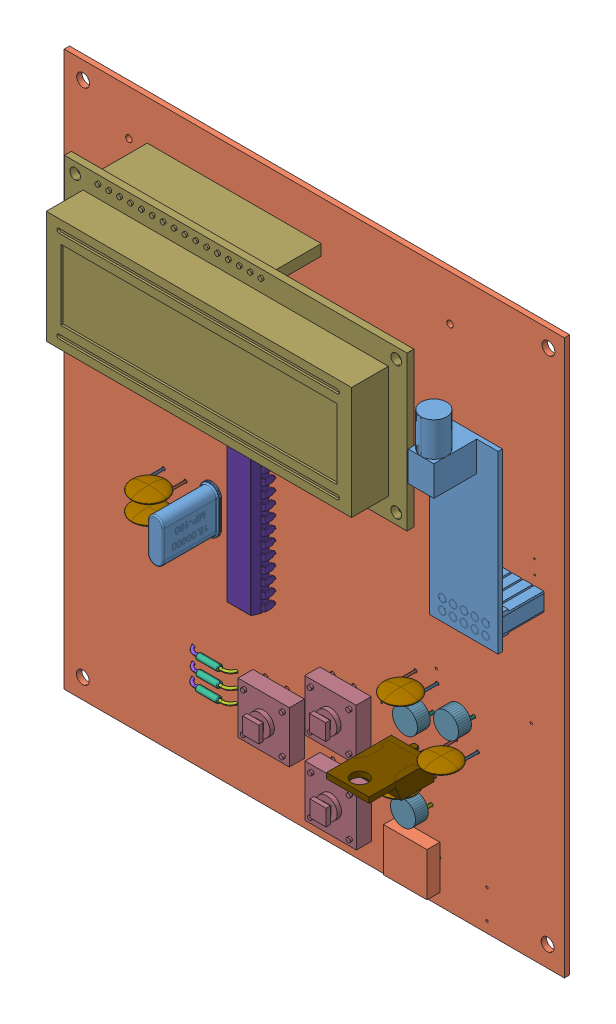
SolidWorks assembly Handheld Terminal Circuit, configuration Default. Lengths in mm.
Overall size (116.81 129.48 32.4).
99 component instances, 20 part files, 0 mates.
Components (placement in the parent):
- Handheld Terminal Circuit.STEP-1: Handheld Terminal Circuit.STEP [Default] at origin size (116.81 129.48 32.4)
  - X1.STEP-1: X1.STEP [Default] at (-24.8494 -12.1588 0.625) x (0 1 0) z (0 0 1) size (11 4.5 15.2)
    - Open CASCADE STEP translator 6.8 1.2.1.STEP-1: Open CASCADE STEP translator 6.8 1.2.1.STEP [Default] at origin size (11 4.5 15.2)
      - Body_1.STEP-1: Body_1.STEP [Default] at (2.5 0 0) x (1 0 0) z (0 -1 0) size (11 15.2 4.5)
  - J1.STEP-1: J1.STEP [Default] at (27.8456 -53.6484 0.625) x (-1 0 0) z (0 0 1) size (10.16 10.16 8.71)
    - Open CASCADE STEP translator 6.8 1.3.1.STEP-1: Open CASCADE STEP translator 6.8 1.3.1.STEP [Default] at origin size (10.16 10.16 8.71)
      - Body_1-0.STEP-1: Body_1-0.STEP [Default] at origin size (10.16 10.16 3)
      - Pin_1.STEP-1: Pin_1.STEP [Default] x (0 -1 0) z (0 0 1) size (1.42 1.42 7.92)
      - Pin_2.STEP-1: Pin_2.STEP [Default] at (5.08 5.08 0) x (0 -1 0) z (0 0 1) size (1.42 1.42 7.92)
  - U2.STEP-1: U2.STEP [Default] at (37.1858 -34.3162 -0.625) x (0 -1 0) z (0 0 -1) size (3.55 6.6 1.62)
    - Open CASCADE STEP translator 6.8 1.4.1.STEP-1: Open CASCADE STEP translator 6.8 1.4.1.STEP [Default] at origin size (3.55 6.6 1.62)
      - Body_1-1.STEP-1: Body_1-1.STEP [Default] at origin size (3.55 6.6 1.62)
  - R1.STEP-1: R1.STEP [Default] at (-50.4294 44.6446 0.625) x (0 -1 0) z (0 0 1) size (10.82 1.37 5.33)
    - Open CASCADE STEP translator 6.8 1.5.1.STEP-1: Open CASCADE STEP translator 6.8 1.5.1.STEP [Default] at origin size (10.82 1.37 5.33)
      - Body_1-2.STEP-1: Body_1-2.STEP [Default] at origin size (5.08 1.37 1.37)
      - Pin_1-3.STEP-1: Pin_1-3.STEP [Default] at origin size (3.2 0.66 4.98)
      - Pin_2-4.STEP-1: Pin_2-4.STEP [Default] at (20.32 0 0) x (-1 0 0) z (0 0 1) size (3.2 0.66 4.98)
  - R2.STEP-1: R2.STEP [Default] at (-20.066 15.8496 0.625) size (10.82 1.37 5.33)
    - Open CASCADE STEP translator 6.8 1.5.1.STEP-1: Open CASCADE STEP translator 6.8 1.5.1.STEP [Default] at origin size (10.82 1.37 5.33)
      - Body_1-2.STEP-1: Body_1-2.STEP [Default] at origin size (5.08 1.37 1.37)
      - Pin_1-3.STEP-1: Pin_1-3.STEP [Default] at origin size (3.2 0.66 4.98)
      - Pin_2-4.STEP-1: Pin_2-4.STEP [Default] at (20.32 0 0) x (-1 0 0) z (0 0 1) size (3.2 0.66 4.98)
  - R3.STEP-1: R3.STEP [Default] at (-19.1008 -43.1546 0.625) x (-1 0 0) z (0 0 1) size (10.82 1.37 5.33)
    - Open CASCADE STEP translator 6.8 1.5.1.STEP-1: Open CASCADE STEP translator 6.8 1.5.1.STEP [Default] at origin size (10.82 1.37 5.33)
      - Body_1-2.STEP-1: Body_1-2.STEP [Default] at origin size (5.08 1.37 1.37)
      - Pin_1-3.STEP-1: Pin_1-3.STEP [Default] at origin size (3.2 0.66 4.98)
      - Pin_2-4.STEP-1: Pin_2-4.STEP [Default] at (20.32 0 0) x (-1 0 0) z (0 0 1) size (3.2 0.66 4.98)
  - R4.STEP-1: R4.STEP [Default] at (-19.1008 -39.751 0.625) x (-1 0 0) z (0 0 1) size (10.82 1.37 5.33)
    - Open CASCADE STEP translator 6.8 1.5.1.STEP-1: Open CASCADE STEP translator 6.8 1.5.1.STEP [Default] at origin size (10.82 1.37 5.33)
      - Body_1-2.STEP-1: Body_1-2.STEP [Default] at origin size (5.08 1.37 1.37)
      - Pin_1-3.STEP-1: Pin_1-3.STEP [Default] at origin size (3.2 0.66 4.98)
      - Pin_2-4.STEP-1: Pin_2-4.STEP [Default] at (20.32 0 0) x (-1 0 0) z (0 0 1) size (3.2 0.66 4.98)
  - R5.STEP-1: R5.STEP [Default] at (-19.2024 -46.2788 0.625) x (-1 0 0) z (0 0 1) size (10.82 1.37 5.33)
    - Open CASCADE STEP translator 6.8 1.5.1.STEP-1: Open CASCADE STEP translator 6.8 1.5.1.STEP [Default] at origin size (10.82 1.37 5.33)
      - Body_1-2.STEP-1: Body_1-2.STEP [Default] at origin size (5.08 1.37 1.37)
      - Pin_1-3.STEP-1: Pin_1-3.STEP [Default] at origin size (3.2 0.66 4.98)
      - Pin_2-4.STEP-1: Pin_2-4.STEP [Default] at (20.32 0 0) x (-1 0 0) z (0 0 1) size (3.2 0.66 4.98)
  - C1.STEP-1: C1.STEP [Default] at (-36.1294 -7.2788 0.625) size (8 2 13.25)
    - Open CASCADE STEP translator 6.8 1.10.1.STEP-1: Open CASCADE STEP translator 6.8 1.10.1.STEP [Default] at origin size (8 2 13.25)
      - Body_1-5.STEP-1: Body_1-5.STEP [Default] at (2.54 -2.54 0) x (0 1 0) z (0 0 1) size (2 8 8)
      - Pin_1-6.STEP-1: Pin_1-6.STEP [Default] x (0 -1 0) z (0 0 1) size (0.5 0.5 9.5)
      - Pin_2-7.STEP-1: Pin_2-7.STEP [Default] at (5.08 5.08 0) x (0 -1 0) z (0 0 1) size (0.5 0.5 9.5)
  - C2.STEP-1: C2.STEP [Default] at (-36.1494 -11.6788 0.625) size (8 2 13.25)
    - Open CASCADE STEP translator 6.8 1.10.1.STEP-1: Open CASCADE STEP translator 6.8 1.10.1.STEP [Default] at origin size (8 2 13.25)
      - Body_1-5.STEP-1: Body_1-5.STEP [Default] at (2.54 -2.54 0) x (0 1 0) z (0 0 1) size (2 8 8)
      - Pin_1-6.STEP-1: Pin_1-6.STEP [Default] x (0 -1 0) z (0 0 1) size (0.5 0.5 9.5)
      - Pin_2-7.STEP-1: Pin_2-7.STEP [Default] at (5.08 5.08 0) x (0 -1 0) z (0 0 1) size (0.5 0.5 9.5)
  - LCD1.STEP-1: LCD1.STEP [Default] at (-19.686 56.143 0.625) size (80 36 24.24)
    - Open CASCADE STEP translator 6.8 1.12.1.STEP-1: Open CASCADE STEP translator 6.8 1.12.1.STEP [Default] at origin size (80 36 24.24)
      - Body_1-8.STEP-1: Body_1-8.STEP [Default] at (13 -17 11) x (1 0 0) z (0 -1 0) size (80 24.24 36)
  - SW1.STEP-1: SW1.STEP [Default] at (-7.2644 -37.4396 0.625) x (0 -1 0) z (0 0 1) size (12.01 12.01 10.01)
    - Open CASCADE STEP translator 6.8 1.13.1.STEP-1: Open CASCADE STEP translator 6.8 1.13.1.STEP [Default] at origin size (12.01 12.01 10.01)
      - Body_1-9.STEP-1: Body_1-9.STEP [Default] at (6 -2 0) x (1 0 0) z (0 -1 0) size (12.01 10.01 12.01)
  - SW2.STEP-1: SW2.STEP [Default] at (8.3378 -29.1306 0.625) x (0 -1 0) z (0 0 1) size (12.01 12.01 10.01)
    - Open CASCADE STEP translator 6.8 1.14.1.STEP-1: Open CASCADE STEP translator 6.8 1.14.1.STEP [Default] at origin size (12.01 12.01 10.01)
      - Body_1-9.STEP-1: Body_1-9.STEP [Default] at (6 -2 0) x (1 0 0) z (0 -1 0) size (12.01 10.01 12.01)
  - SW3.STEP-1: SW3.STEP [Default] at (8.411 -46.3848 0.625) x (0 -1 0) z (0 0 1) size (12.01 12.01 10.01)
    - Open CASCADE STEP translator 6.8 1.15.1.STEP-1: Open CASCADE STEP translator 6.8 1.15.1.STEP [Default] at origin size (12.01 12.01 10.01)
      - Body_1-9.STEP-1: Body_1-9.STEP [Default] at (6 -2 0) x (1 0 0) z (0 -1 0) size (12.01 10.01 12.01)
  - C5.STEP-1: C5.STEP [Default] at (37.2474 -27.8864 0.625) x (-1 0 0) z (0 0 1) size (8 2 13.25)
    - Open CASCADE STEP translator 6.8 1.10.1.STEP-1: Open CASCADE STEP translator 6.8 1.10.1.STEP [Default] at origin size (8 2 13.25)
      - Body_1-5.STEP-1: Body_1-5.STEP [Default] at (2.54 -2.54 0) x (0 1 0) z (0 0 1) size (2 8 8)
      - Pin_1-6.STEP-1: Pin_1-6.STEP [Default] x (0 -1 0) z (0 0 1) size (0.5 0.5 9.5)
      - Pin_2-7.STEP-1: Pin_2-7.STEP [Default] at (5.08 5.08 0) x (0 -1 0) z (0 0 1) size (0.5 0.5 9.5)
  - C6.STEP-1: C6.STEP [Default] at (36.3584 -21.13 0.625) x (-1 0 0) z (0 0 1) size (5.84 5.84 8.33)
    - Open CASCADE STEP translator 6.8 1.17.1.STEP-1: Open CASCADE STEP translator 6.8 1.17.1.STEP [Default] at origin size (5.84 5.84 8.33)
      - Body_1-10.STEP-1: Body_1-10.STEP [Default] at origin size (5.84 5.84 3)
      - Pin_1-11.STEP-1: Pin_1-11.STEP [Default] x (0 -1 0) z (0 0 1) size (0.66 0.66 7.16)
      - Pin_2-12.STEP-1: Pin_2-12.STEP [Default] at (3.175 3.175 0) x (0 -1 0) z (0 0 1) size (0.66 0.66 7.16)
  - U1.STEP-1: U1.STEP [Default] at (-17.9284 11.5356 0.625) x (0 -1 0) z (0 0 1) size (35.56 7.92 7.75)
    - Open CASCADE STEP translator 6.8 1.18.1.STEP-1: Open CASCADE STEP translator 6.8 1.18.1.STEP [Default] at origin size (35.56 7.92 7.75)
      - Body_1-13.STEP-1: Body_1-13.STEP [Default] at (16.5 3.8 0) x (0 1 0) z (1 0 0) size (7.92 7.75 35.56)
  - U3.STEP-1: U3.STEP [Default] at (25.5126 -34.084 0.625) size (9.97 4.45 28.62)
    - Open CASCADE STEP translator 6.8 1.19.1.STEP-1: Open CASCADE STEP translator 6.8 1.19.1.STEP [Default] at origin size (9.97 4.45 28.62)
      - Body_1-14.STEP-1: Body_1-14.STEP [Default] at (0 3 3.5) x (1 0 0) z (0 -1 0) size (9.97 28.62 4.45)
  - C7.STEP-1: C7.STEP [Default] at (23.252 -43.9138 0.625) size (5.84 5.84 8.33)
    - Open CASCADE STEP translator 6.8 1.17.1.STEP-1: Open CASCADE STEP translator 6.8 1.17.1.STEP [Default] at origin size (5.84 5.84 8.33)
      - Body_1-10.STEP-1: Body_1-10.STEP [Default] at origin size (5.84 5.84 3)
      - Pin_1-11.STEP-1: Pin_1-11.STEP [Default] x (0 -1 0) z (0 0 1) size (0.66 0.66 7.16)
      - Pin_2-12.STEP-1: Pin_2-12.STEP [Default] at (3.175 3.175 0) x (0 -1 0) z (0 0 1) size (0.66 0.66 7.16)
  - C8.STEP-1: C8.STEP [Default] at (22.1344 -37.8178 0.625) size (8 2 13.25)
    - Open CASCADE STEP translator 6.8 1.10.1.STEP-1: Open CASCADE STEP translator 6.8 1.10.1.STEP [Default] at origin size (8 2 13.25)
      - Body_1-5.STEP-1: Body_1-5.STEP [Default] at (2.54 -2.54 0) x (0 1 0) z (0 0 1) size (2 8 8)
      - Pin_1-6.STEP-1: Pin_1-6.STEP [Default] x (0 -1 0) z (0 0 1) size (0.5 0.5 9.5)
      - Pin_2-7.STEP-1: Pin_2-7.STEP [Default] at (5.08 5.08 0) x (0 -1 0) z (0 0 1) size (0.5 0.5 9.5)
  - C9.STEP-1: C9.STEP [Default] at (26.7572 -25.067 0.625) x (-1 0 0) z (0 0 1) size (5.84 5.84 8.33)
    - Open CASCADE STEP translator 6.8 1.17.1.STEP-1: Open CASCADE STEP translator 6.8 1.17.1.STEP [Default] at origin size (5.84 5.84 8.33)
      - Body_1-10.STEP-1: Body_1-10.STEP [Default] at origin size (5.84 5.84 3)
      - Pin_1-11.STEP-1: Pin_1-11.STEP [Default] x (0 -1 0) z (0 0 1) size (0.66 0.66 7.16)
      - Pin_2-12.STEP-1: Pin_2-12.STEP [Default] at (3.175 3.175 0) x (0 -1 0) z (0 0 1) size (0.66 0.66 7.16)
  - C10.STEP-1: C10.STEP [Default] at (27.7732 -18.7424 0.625) x (-1 0 0) z (0 0 1) size (8 2 13.25)
    - Open CASCADE STEP translator 6.8 1.10.1.STEP-1: Open CASCADE STEP translator 6.8 1.10.1.STEP [Default] at origin size (8 2 13.25)
      - Body_1-5.STEP-1: Body_1-5.STEP [Default] at (2.54 -2.54 0) x (0 1 0) z (0 0 1) size (2 8 8)
      - Pin_1-6.STEP-1: Pin_1-6.STEP [Default] x (0 -1 0) z (0 0 1) size (0.5 0.5 9.5)
      - Pin_2-7.STEP-1: Pin_2-7.STEP [Default] at (5.08 5.08 0) x (0 -1 0) z (0 0 1) size (0.5 0.5 9.5)
  - RF24.STEP-1: RF24.STEP [Default] at (46.3962 10.2222 0.625) size (16 49 24.9)
    - Open CASCADE STEP translator 6.8 1.24.1.STEP-1: Open CASCADE STEP translator 6.8 1.24.1.STEP [Default] at origin size (16 49 24.9)
      - Body_1-15.STEP-1: Body_1-15.STEP [Default] at (0 0 8.2) x (1 0 0) z (0 -1 0) size (16 24.9 49)
  - Layer_1.STEP-1: Layer_1.STEP [Default] at origin size (116.81 129.48 1.25)
